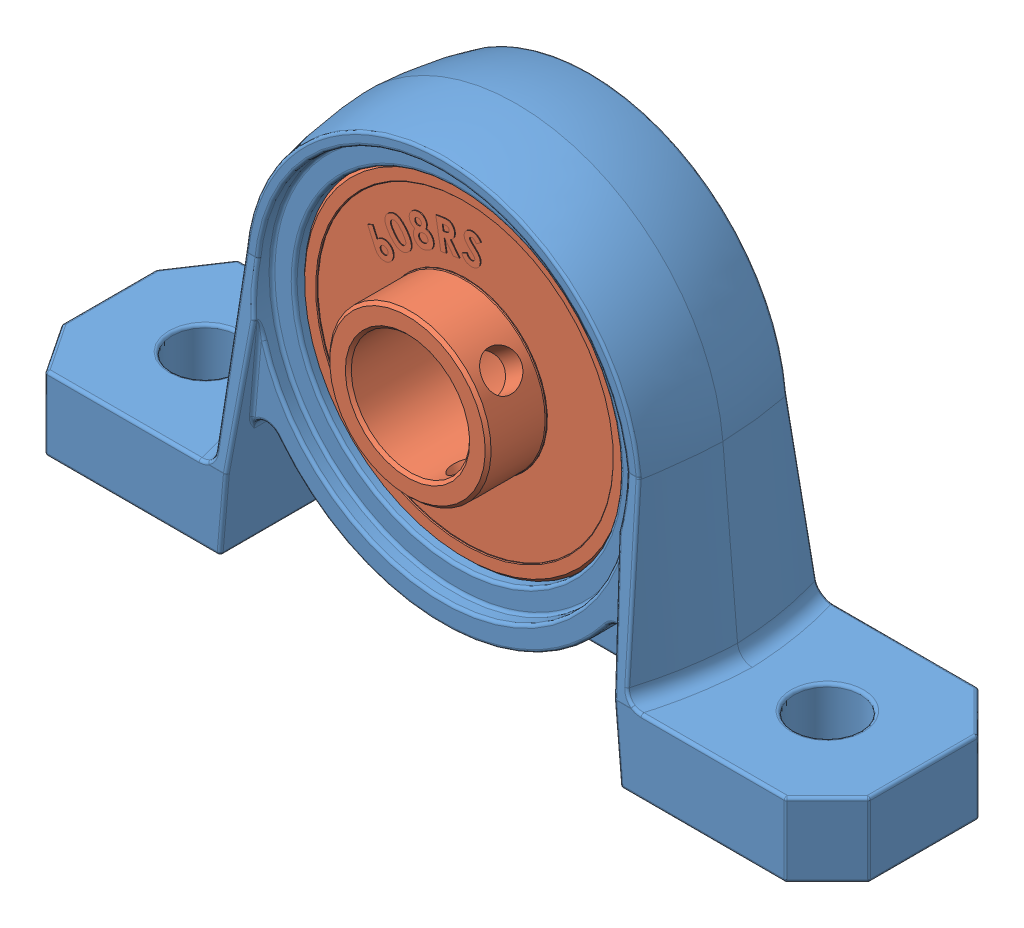
SolidWorks assembly KP081, configuration 預設. Lengths in mm.
Overall size (55 40.89 13.95).
2 component instances, 2 part files, 0 mates.
Components (placement in the parent):
- KP08_1-1: KP08_1 [預設] at (2.2899 16 0) size (55 40.89 13.19)
- 608RS-1: 608RS [預設] at (2.2899 16 -3.5) x (0.16403 0.986455 0) z (0 0 1) size (22 22 10.85)
